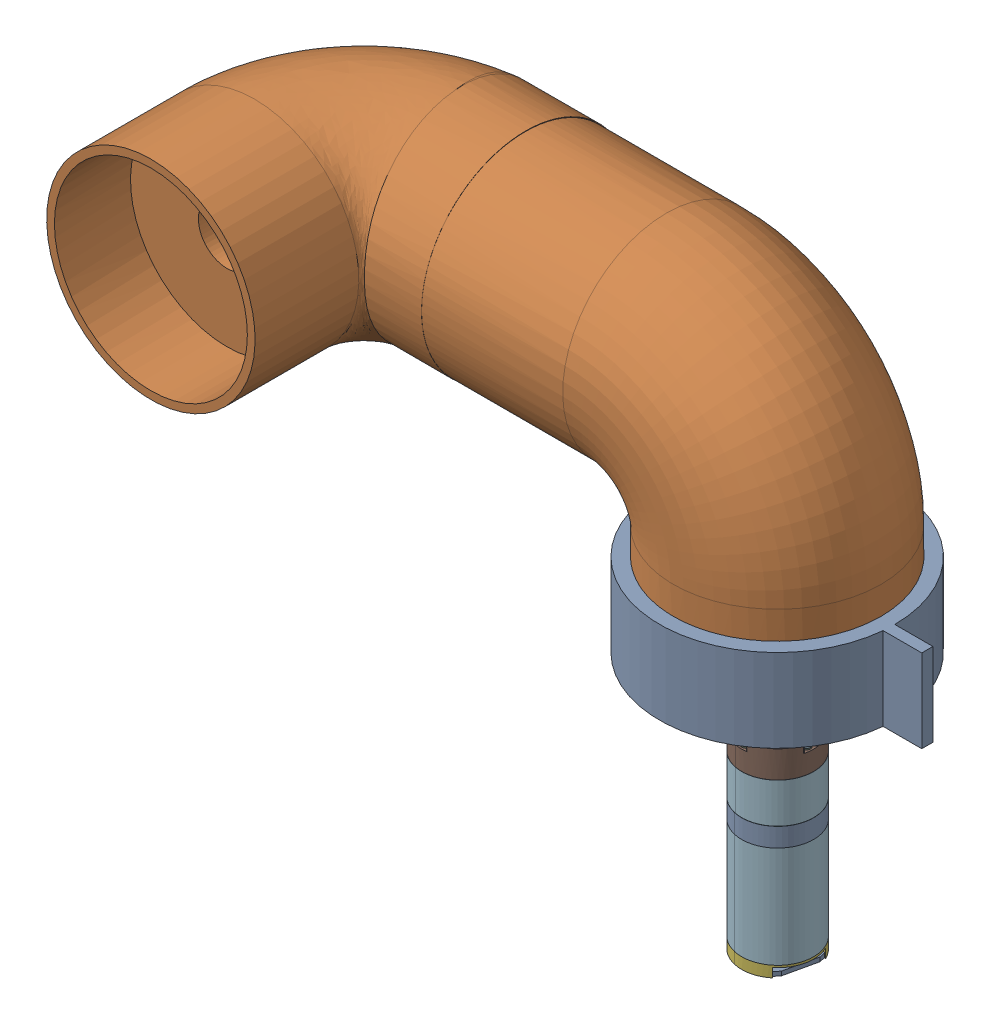
SolidWorks assembly arm_2_assembly, configuration Default. Lengths in mm.
Overall size (487.84 420.98 237.84).
7 component instances, 7 part files, 13 mates.
Components (placement in the parent):
- rotary_joint-1: rotary_joint [Default] at (15.2307 185.65 -97.8361) x (-1 0 0) z (0 0 -1) size (197.58 60 170)
- arm2-1: arm2 [Default] at (15.3058 225.65 -98.1098) x (0 -1 0) z (0 0 -1) size (195.33 450.26 228.44)
- bushing hub-1: bushing hub [9859T718] at (15.3058 256.125 -98.1098) x (0 -1 0) z (-0.554532 0 0.832162) size (35.75 63.5 63.5)
- arm 2 shaft-1: arm 2 shaft [Default] at (15.3058 172 -98.1098) x (0.999959 0 0.009091) z (-0.009091 0 0.999959) size (20 100 20)
- arm ball bearing-1: arm ball bearing [5972K119] at (15.2307 215.65 -97.8361) x (0.999959 0 0.009091) z (0 -1 0) size (52 52 15)
- arm 1 shaft coupler-1: arm 1 shaft coupler [6853N141] at (15.3058 180.5169 -98.1098) x (-0.843268 0 -0.537493) z (0 -1 0) size (38.97 38.89 48.13)
- arm 1 motor-1: arm 1 motor [Default] at (-36.1378 133.55 -43.2276) x (-0.184165 0 0.982895) z (0 1 0) size (52 52 172)
Mates (geometry in assembly coordinates):
- Concentric7: concentric anti-aligned: cylinder of rotary_joint-1 through (15.2307 245.65 -97.8361) axis (0 -1 0) radius 26; cylinder of arm2-1 through (15.2307 225.65 -97.8361) axis (0 1 0) radius 75
- Concentric8: concentric aligned: circle of arm2-1; circle of bushing hub-1
- Coincident6: coincident aligned: plane of arm2-1; plane of bushing hub-1 through (-11.1154 265.65 -115.7162) normal (0 -1 0)
- Concentric9: concentric anti-aligned: circle of bushing hub-1; circle of arm 2 shaft-1
- Coincident8: coincident aligned: plane of bushing hub-1 through (15.3058 272 -98.1098) normal (0 1 0); plane of arm 2 shaft-1 through (15.3058 272 -98.1098) normal (0 1 0)
- Coincident9: coincident anti-aligned: plane of rotary_joint-1 through (15.2307 225.65 -97.8361) normal (0 1 0); plane of arm2-1 through (15.2307 225.65 -97.8361) normal (0 -1 0)
- Concentric10: concentric anti-aligned: circle of rotary_joint-1; circle of ball bearing-1
- Distance1: distance = 22.5 mm aligned: plane of arm ball bearing-1 through (15.0012 223.15 -72.5871) normal (0 1 0); plane of rotary_joint-1 through (15.2307 245.65 -97.8361) normal (0 1 0)
- Concentric11: concentric aligned: circle of arm 2 shaft-1; circle of arm 1 shaft coupler-1
- Concentric12: concentric aligned: circle of arm 2 shaft-1; circle of arm 1 shaft coupler-1
- Coincident14: coincident anti-aligned: plane of arm 2 shaft-1 through (15.3058 172 -98.1098) normal (0 -1 0); plane of arm 1 shaft coupler-1 through (18.5307 172 -103.1694) normal (0 1 0)
- Concentric13: concentric anti-aligned: circle of arm 1 shaft coupler-1; circle of arm 1 motor-1
- Coincident15: coincident anti-aligned: plane of arm 2 shaft-1 through (15.3058 172 -98.1098) normal (0 -1 0); plane of arm 1 motor-1 through (15.3058 172 -98.1098) normal (0 1 0)
